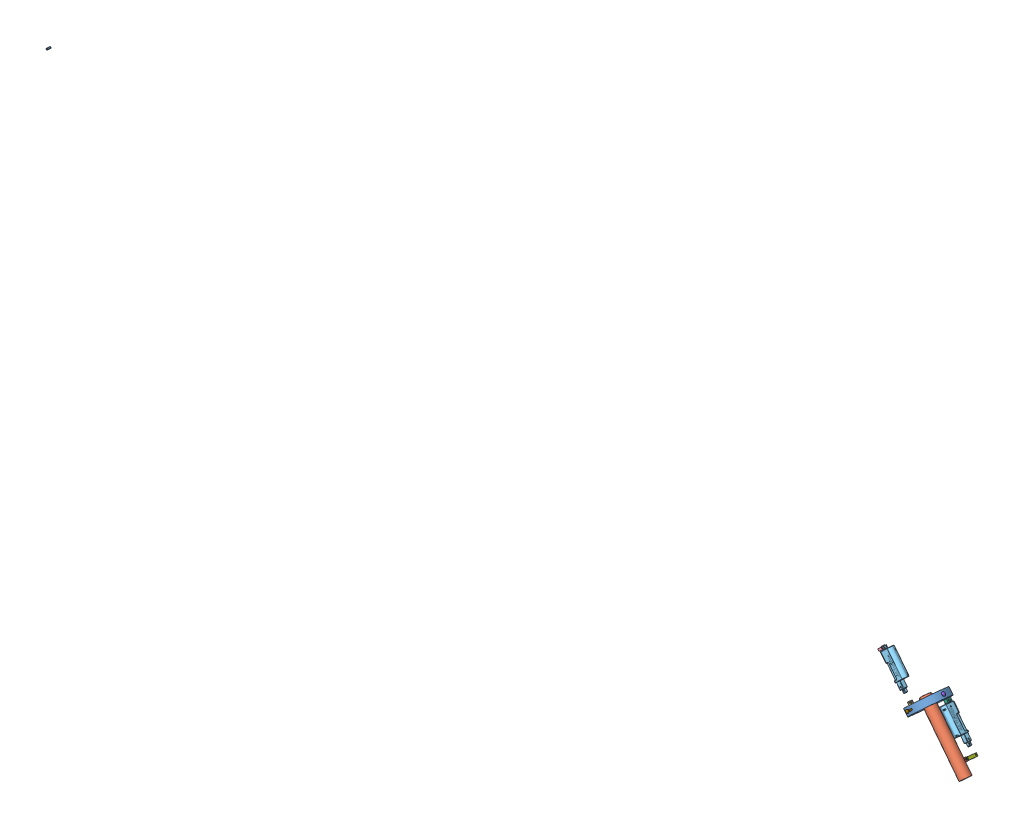
SolidWorks assembly Assembly, configuration Default. Lengths in mm.
Overall size (2641.35 486.71 132.64).
19 component instances, 13 part files, 40 mates.
Components (placement in the parent):
- BodyTube-2: BodyTube [Default] at (115.4207 234.3467 -37.6347) x (0.722931 0.680008 -0.122307) z (0.03763 0.138007 0.989716) size (249.72 330.2 287.26) (hidden)
- GimbalRing-2: GimbalRing [Default] at (3.684 350.9755 -49.6492) x (-0.03763 -0.138007 -0.989716) z (0.722931 0.680008 -0.122307) size (101.6 19.05 101.6)
- EngineCasing-2: EngineCasing [Default] at (115.3951 234.3734 -37.6375) x (0.03763 0.138007 0.989716) z (-0.722931 -0.680008 0.122307) size (29 186.69 29)
- Actuator Fastener Gimbal-2: Actuator Fastener Gimbal [Default] at (-49.3521 330.3581 -44.2446) x (-0.03763 -0.138007 -0.989716) z (0.722931 0.680008 -0.122307) size (7.62 9.14 7.62)
- Actuator Fastener BodyTube-3: Actuator Fastener BodyTube [Default] at (-143.7128 418.6943 -51.6777) x (-0.03763 -0.138007 -0.989716) z (0.689894 -0.720099 0.074181) size (9.65 18.73 5.84)
- p16_50mm_in(Actuator)-1: p16_50mm_in(Actuator) [Default] at (-138.176 413.559 -52.9823) x (-0.722931 -0.680008 0.122307) z (0.689894 -0.720099 0.074181) size (36.18 20.01 105.9)
- Actuator 2 Fastoner to Gimbal Ring-1: Actuator 2 Fastoner to Gimbal Ring [Default] at (-0.3835 342.2516 -96.5069) x (-0.722931 -0.680008 0.122307) z (0.03763 0.138007 0.989716) size (9.65 8.38 12.19)
- p16_50mm_in(Actuator)-3: p16_50mm_in(Actuator) [Default] at (8.0462 335.8362 -108.037) x (-0.03763 -0.138007 -0.989716) z (0.689894 -0.720099 0.074181) size (36.18 20.01 105.9)
- Actuator 2 pivot pin-1: Actuator 2 pivot pin [Default] at (92.1174 254.8716 -96.5649) x (-0.03763 -0.138007 -0.989716) z (-0.722931 -0.680008 0.122307) size (35.81 7.62 8.64)
- Quarter 20 bolt - Gimbal Ring to Engine Casing-1: Quarter 20 bolt - Gimbal Ring to Engine Casing [Default] at (-39.8117 323.1023 -44.1088) x (0.395027 -0.261568 0.880645) z (0.722931 0.680008 -0.122307) size (10.16 10.16 39.59)
- Quarter 20 bolt - Gimbal Ring to Engine Casing-2: Quarter 20 bolt - Gimbal Ring to Engine Casing [Default] at (33.9454 392.4802 -56.5873) x (-0.560919 0.680997 0.470758) z (-0.722931 -0.680008 0.122307) size (10.16 10.16 39.59)
- Quarter 20 bolt - Body Tube to Gimbal Ring - Copy-2: Quarter 20 bolt - Body Tube to Gimbal Ring - Copy [Default] at (-5.1078 349.5701 -109.4292) x (-0.114866 0.98445 -0.132905) z (-0.03763 -0.138007 -0.989716) size (8.89 8.89 18.8)
- Quarter 20 bolt - Body Tube to Gimbal Ring - Copy-3: Quarter 20 bolt - Body Tube to Gimbal Ring - Copy [Default] at (-0.6155 366.0453 8.7231) x (0.983835 0.168408 -0.060889) z (0.03763 0.138007 0.989716) size (8.89 8.89 18.8)
- Actuator Fastoning pin-1: Actuator Fastoning pin [Default] at (2.3988 337.7622 -97.4818) x (0.534326 -0.438025 0.722931) z (-0.722931 -0.680008 0.122307) size (4.83 4.83 11.76)
- Actuator Fastoning pin-2: Actuator Fastoning pin [Default] at (-2512.5166 706.8126 -54.8195) size (4.83 4.83 11.76)
- Actuator Fastoning pin-3: Actuator Fastoning pin [Default] at (92.7769 258.2528 -61.4078) x (0.624519 -0.718856 -0.305323) z (0.722931 0.680008 -0.122307) size (4.83 4.83 11.76)
- Part1^Assembly-1: Part1^Assembly [Default] at origin (virtual)
- Actuator Fastoning pin-4: Actuator Fastoning pin [Default] at (-133.5369 424.5004 -50.5782) x (0.594129 -0.799444 0.088886) z (0.03763 0.138007 0.989716) size (4.83 4.83 11.76)
- Actuator 2 Fastener Engine Casing(#2)-1: Actuator 2 Fastener Engine Casing(#2) [Default] at (94.5326 256.1476 -54.1234) x (0.689894 -0.720099 0.074181) z (-0.03763 -0.138007 -0.989716) size (9.14 6.6 9.91)
Mates (geometry in assembly coordinates):
- Gimbal Hole Allignment: concentric: cylinder of BodyTube-2 through (-0.4722 366.5712 12.4939) axis (0.03763 0.138007 0.989716) radius 2.5527; cylinder of GimbalRing-2 through (-0.9501 364.8185 -0.0755) axis (-0.03763 -0.138007 -0.989716) radius 1.905
- BT Hole Allignment: coincident: plane of BodyTube-2 through (115.4207 234.3467 -37.6347) normal (0.03763 0.138007 0.989716); plane of GimbalRing-2 through (3.684 350.9755 -49.6492) normal (-0.03763 -0.138007 -0.989716)
- Engine Hole Allignment: concentric: cylinder of GimbalRing-2 through (-25.8403 336.2442 -46.4726) axis (-0.722931 -0.680008 0.122307) radius 2.5527; cylinder of EngineCasing-2 through (7.1362 367.2627 -52.0516) axis (0.722931 0.680008 -0.122307) radius 1.905
- GR to Casing Allignment: coincident: plane of GimbalRing-2 through (3.684 350.9755 -49.6492) normal (0.722931 0.680008 -0.122307); plane of EngineCasing-2 through (115.3951 234.3734 -37.6375) normal (-0.722931 -0.680008 0.122307)
- keeping gimbal zero: parallel: plane of BodyTube-2 through (-112.3824 472.1235 -62.1293) normal (-0.689894 0.720099 -0.074181); plane of GimbalRing-2 through (-9.4585 364.6934 -51.0624) normal (-0.689894 0.720099 -0.074181)
- keeping engine casing zero: parallel: plane of GimbalRing-2 through (-9.4585 364.6934 -51.0624) normal (-0.689894 0.720099 -0.074181); plane of EngineCasing-2 through (-13.4013 368.8087 -51.4863) normal (-0.689894 0.720099 -0.074181)
- A1 Fixture on GR: coincident: plane of GimbalRing-2 through (-9.4585 364.6934 -51.0624) normal (-0.689894 0.720099 -0.074181); plane of Actuator Fastener Gimbal-2 through (-42.1361 334.3523 -41.6872) normal (0.689894 -0.720099 0.074181)
- A1FixGR over pin holes: coincident: plane of EngineCasing-2 through (115.3951 234.3734 -37.6375) normal (0.03763 0.138007 0.989716); plane of Actuator Fastener Gimbal-2 through (-49.3713 330.288 -44.7474) normal (-0.03763 -0.138007 -0.989716)
- Center A1Fix on GR: distance = 49.2125 mm: plane of Actuator Fastener Gimbal-2 through (-46.5978 332.9489 -44.7106) normal (-0.722931 -0.680008 0.122307); plane of EngineCasing-2 through (115.3951 234.3734 -37.6375) normal (-0.722931 -0.680008 0.122307)
- Center A1 in A1FixGR: coincident: plane of Actuator Fastener Gimbal-2 through (-49.3713 330.288 -44.7474) normal (-0.03763 -0.138007 -0.989716); plane of p16_50mm_in(Actuator)-1 through (-138.176 413.559 -52.9823) normal (-0.03763 -0.138007 -0.989716)
- keeping A1 at zero: parallel: plane of Actuator Fastener Gimbal-2 through (-49.3521 330.3581 -44.2446) normal (-0.722931 -0.680008 0.122307); plane of p16_50mm_in(Actuator)-1 through (-121.6581 403.8372 -46.1924) normal (-0.722931 -0.680008 0.122307)
- Weld A1FixBT to BT: concentric: cylinder of BodyTube-2 through (-29.1466 385.2435 -53.1794) axis (-0.689894 0.720099 -0.074181) radius 62.7063; cylinder of Actuator Fastener BodyTube-3 through (-96.1858 455.2178 -60.3878) axis (-0.689894 0.720099 -0.074181) radius 62.738
- A1FixBT 25mm up: coincident: plane of Actuator Fastener BodyTube-3 through (-141.6977 416.5909 -51.461) normal (0.689894 -0.720099 0.074181); plane of assembly through (-277.0344 289.1635 -29.7882) normal (-0.689894 0.720099 -0.074181)
- A1 centered in A1FixBT: coincident: plane of Actuator Fastener BodyTube-3 through (-143.7802 418.4471 -53.4509) normal (0.03763 0.138007 0.989716); plane of p16_50mm_in(Actuator)-1 through (-138.176 413.559 -52.9823) normal (-0.03763 -0.138007 -0.989716)
- A1FixBT concentric A1: concentric: circle of Actuator Fastener BodyTube-3; cylinder of p16_50mm_in(Actuator)-1 through (-133.8403 423.3875 -58.5592) axis (0.03763 0.138007 0.989716) radius 2.125
- A1FixGR fixed over pin hole: coincident: plane of EngineCasing-2 through (115.3951 234.3734 -37.6375) normal (-0.722931 -0.680008 0.122307); plane of Actuator 2 Fastoner to Gimbal Ring-1 through (1.8878 344.388 -96.8911) normal (-0.722931 -0.680008 0.122307)
- A2FixGR centered over GR: distance = 49.2125 mm: plane of EngineCasing-2 through (115.3951 234.3734 -37.6375) normal (0.03763 0.138007 0.989716); plane of Actuator 2 Fastoner to Gimbal Ring-1 through (-0.4392 342.0474 -97.9714) normal (0.03763 0.138007 0.989716)
- A2FixGR fixed to GR: coincident: plane of GimbalRing-2 through (3.684 350.9755 -49.6492) normal (0.689894 -0.720099 0.074181); plane of Actuator 2 Fastoner to Gimbal Ring-1 through (-0.3835 342.2516 -96.5069) normal (-0.689894 0.720099 -0.074181)
- A2FixGR concentric A2: concentric: circle of Actuator 2 Fastoner to Gimbal Ring-1; cylinder of p16_50mm_in(Actuator)-3 through (8.2285 343.2457 -98.468) axis (-0.722931 -0.680008 0.122307) radius 2.125
- A2 centered A2FixGR: coincident: plane of Actuator 2 Fastoner to Gimbal Ring-1 through (1.8878 344.388 -96.8911) normal (-0.722931 -0.680008 0.122307); plane of p16_50mm_in(Actuator)-3 through (8.0462 335.8362 -108.037) normal (0.722931 0.680008 -0.122307)
- keeping A2 zero: parallel: plane of Actuator 2 Fastoner to Gimbal Ring-1 through (3.8966 334.0249 -103.1769) normal (-0.03763 -0.138007 -0.989716); plane of p16_50mm_in(Actuator)-3 through (16.9169 318.7673 -101.4474) normal (-0.03763 -0.138007 -0.989716)
- Concentric4: concentric: cylinder of GimbalRing-2 through (20.0658 379.4247 -54.2391) axis (0.722931 0.680008 -0.122307) radius 2.5527; cylinder of Quarter 20 bolt - Gimbal Ring to Engine Casing-1 through (-13.3698 347.9743 -48.5824) axis (-0.722931 -0.680008 0.122307) radius 2.2225
- Tangent2: tangent: cylinder of EngineCasing-2 through (-13.4013 368.8087 -51.4863) axis (0.689894 -0.720099 0.074181) radius 14.5; plane of Quarter 20 bolt - Gimbal Ring to Engine Casing-1 through (-13.3698 347.9743 -48.5824) normal (0.722931 0.680008 -0.122307)
- Concentric5: concentric: cylinder of GimbalRing-2 through (-25.8403 336.2442 -46.4726) axis (-0.722931 -0.680008 0.122307) radius 2.5527; cylinder of Quarter 20 bolt - Gimbal Ring to Engine Casing-2 through (7.5034 367.6082 -52.1137) axis (0.722931 0.680008 -0.122307) radius 2.2225
- Coincident3: coincident: plane of EngineCasing-2 through (7.1362 367.2627 -52.0516) normal (0.722931 0.680008 -0.122307); plane of Quarter 20 bolt - Gimbal Ring to Engine Casing-2 through (7.1362 367.2627 -52.0516) normal (-0.722931 -0.680008 0.122307)
- Concentric7: concentric: cylinder of BodyTube-2 through (-5.2512 349.0443 -113.2) axis (-0.03763 -0.138007 -0.989716) radius 2.5527; cylinder of Quarter 20 bolt - Body Tube to Gimbal Ring - Copy-2 through (-4.7733 350.7969 -100.6306) axis (-0.03763 -0.138007 -0.989716) radius 2.2225
- Tangent4: tangent: cylinder of GimbalRing-2 through (-9.4585 364.6934 -51.0624) axis (0.689894 -0.720099 0.074181) radius 50.8; plane of Quarter 20 bolt - Body Tube to Gimbal Ring - Copy-2 through (-4.7733 350.7969 -100.6306) normal (0.03763 0.138007 0.989716)
- Concentric10: concentric: cylinder of BodyTube-2 through (-0.4722 366.5712 12.4939) axis (0.03763 0.138007 0.989716) radius 2.5527; cylinder of Quarter 20 bolt - Body Tube to Gimbal Ring - Copy-3 through (-0.9501 364.8185 -0.0755) axis (0.03763 0.138007 0.989716) radius 2.2225
- Tangent5: tangent: cylinder of GimbalRing-2 through (-9.4585 364.6934 -51.0624) axis (0.689894 -0.720099 0.074181) radius 50.8; plane of Quarter 20 bolt - Body Tube to Gimbal Ring - Copy-3 through (-0.9501 364.8185 -0.0755) normal (-0.03763 -0.138007 -0.989716)
- Concentric11: concentric: cylinder of p16_50mm_in(Actuator)-3 through (8.2285 343.2457 -98.468) axis (-0.722931 -0.680008 0.122307) radius 2.125; cylinder of Actuator Fastoning pin-1 through (8.8257 343.8074 -98.5691) axis (-0.722931 -0.680008 0.122307) radius 2.032
- Coincident6: coincident: plane of Actuator 2 Fastoner to Gimbal Ring-1 through (10.8743 340.5884 -104.3574) normal (0.722931 0.680008 -0.122307); plane of Actuator Fastoning pin-1 through (8.8257 343.8074 -98.5691) normal (-0.722931 -0.680008 0.122307)
- Concentric14: concentric: cylinder of p16_50mm_in(Actuator)-1 through (-133.8403 423.3875 -58.5592) axis (0.03763 0.138007 0.989716) radius 2.125; cylinder of Actuator Fastoning pin-4 through (-133.8714 423.2735 -59.3767) axis (0.03763 0.138007 0.989716) radius 2.032
- Concentric15: concentric: cylinder of EngineCasing-2 through (-13.4013 368.8087 -51.4863) axis (0.689894 -0.720099 0.074181) radius 14.5; cylinder of Actuator 2 Fastener Engine Casing(#2)-1 through (94.7045 255.9699 -39.8622) axis (-0.689894 0.720099 -0.074181) radius 14.478
- Coincident7: coincident: plane of Actuator 2 Fastener Engine Casing(#2)-1 through (92.2783 258.5006 -54.3658) normal (-0.689894 0.720099 -0.074181); plane of assembly through (-87.2831 91.1045 -9.3851) normal (0.689894 -0.720099 0.074181)
- Concentric16: concentric: cylinder of Actuator Fastoning pin-3 through (86.35 252.2075 -60.3204) axis (0.722931 0.680008 -0.122307) radius 2.032; circle of Actuator 2 Fastener Engine Casing(#2)-1
- Coincident8: coincident: plane of Actuator Fastoning pin-3 through (92.7769 258.2528 -61.4078) normal (0.722931 0.680008 -0.122307); plane of Actuator 2 Fastener Engine Casing(#2)-1 through (90.1787 261.9329 -56.3044) normal (-0.722931 -0.680008 0.122307)
- Parallel2: parallel: plane of GimbalRing-2 through (-19.2691 329.3852 -45.766) normal (0.722931 0.680008 -0.122307); plane of Actuator 2 Fastener Engine Casing(#2)-1 through (93.2742 254.9638 -53.9105) normal (-0.722931 -0.680008 0.122307)
- Concentric17: concentric: cylinder of Actuator 2 pivot pin-1 through (93.8786 259.2891 -61.5941) axis (-0.722931 -0.680008 0.122307) radius 2.159; cylinder of Actuator Fastoning pin-3 through (86.35 252.2075 -60.3204) axis (0.722931 0.680008 -0.122307) radius 2.032
- Coincident11: coincident: plane of Actuator 2 pivot pin-1 through (92.5508 254.4192 -96.5183) normal (0.689894 -0.720099 0.074181); plane of Actuator 2 Fastener Engine Casing(#2)-1 through (92.2783 258.5006 -54.3658) normal (-0.689894 0.720099 -0.074181)
- Coincident12: coincident: plane of Actuator 2 pivot pin-1 through (88.9957 251.9354 -96.0368) normal (0.722931 0.680008 -0.122307); plane of Actuator 2 Fastener Engine Casing(#2)-1 through (93.2742 254.9638 -53.9105) normal (-0.722931 -0.680008 0.122307)
